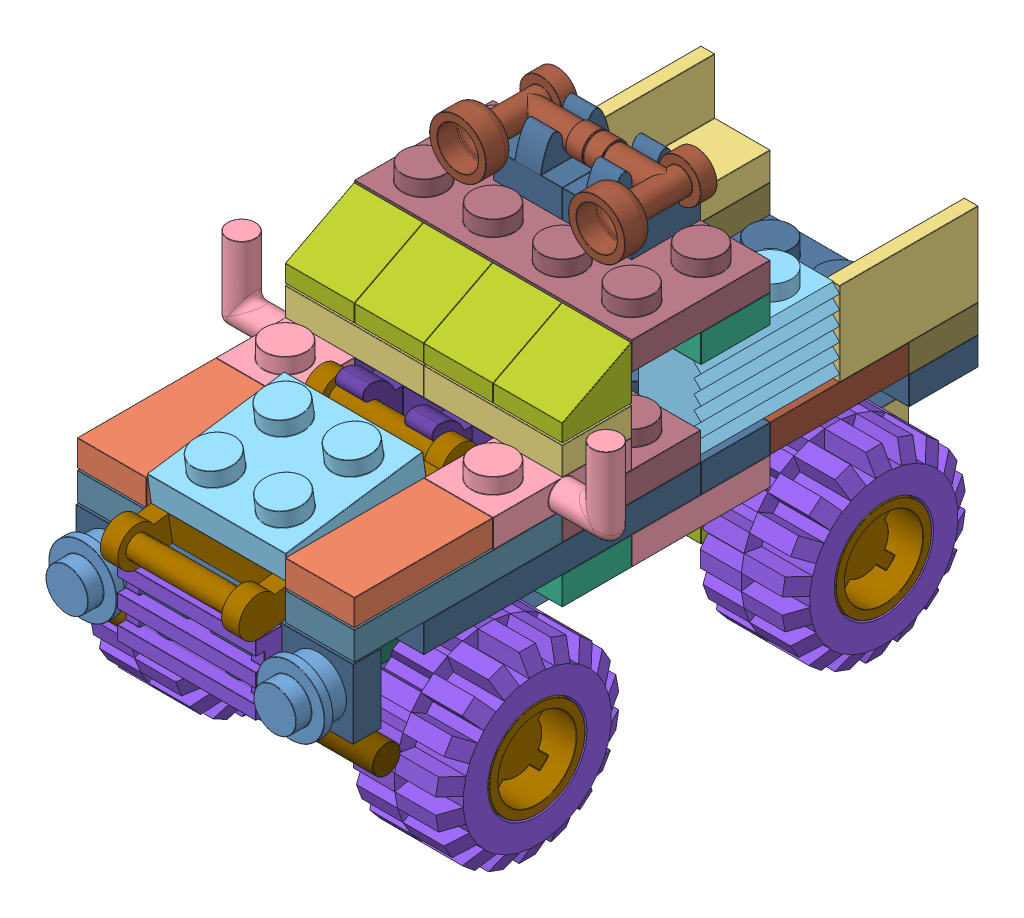
SolidWorks assembly Yellow Truck, configuration Default. Lengths in mm.
Overall size (45.06 54.34 77.31).
66 component instances, 29 part files, 149 mates.
Components (placement in the parent):
- 4211406-1: 4211406 [Default] at (-6.4803 -11.5963 11.298) size (15.92 5.02 63.68)
- 379526-1: 379526 [Default] at (-14.4403 -8.3763 3.338) size (15.92 5.02 47.76)
- 302326-1: 302326 [Default] at (-14.4403 -8.3763 -44.422) size (15.92 5.02 7.96)
- 4211094-1: 4211094 [Default] at (-22.4003 -5.1563 -12.582) size (15.92 5.02 15.92)
- 4211094-2: 4211094 [Default] at (-6.4803 -5.1563 -12.582) size (15.92 5.02 15.92)
- 302224-1: 302224 [Default] at (-14.4403 -5.1563 -28.502) size (15.92 5.02 15.92)
- 4210635-1: 4210635 [Default] at (-14.4403 -5.1563 -4.622) x (-1 0 0) z (0 0 -1) size (15.92 5.02 15.92)
- 4210635-2: 4210635 [Default] at (-6.4803 -5.1563 -4.622) x (0 0 1) z (-1 0 0) size (15.92 5.02 15.92)
- Wheel Assembly-1: Wheel Assembly [Default] at (-7.1213 -14.0712 6.9296) size (42 29.52 29.52)
  - 4211504-1: 4211504 [Default] at (-7.319 -0.7451 4.3684) size (27.68 6.09 15.92)
  - 4514560-1: 4514560 [Default] at (-18.469 0.3282 0.3884) x (1 0 0) z (0 -0.782052 0.623213) size (11.74 21 21)
  - 4514560-2: 4514560 [Default] at (11.791 0.3282 0.3884) size (11.74 21 21)
  - 4170457-1: 4170457 [Default] at (-12.499 0.3282 0.3884) x (0 1 0) z (0 0 1) size (11 11.84 11)
  - 4170457-2: 4170457 [Default] at (5.821 0.3282 0.3884) x (0 -1 0) z (0 0 1) size (11 11.84 11)
- Wheel Assembly-2: Wheel Assembly [Default] at (-7.1213 -14.0712 -32.8704) size (42 29.52 29.52)
  - 4211504-1: 4211504 [Default] at (-7.319 -0.7451 4.3684) size (27.68 6.09 15.92)
  - 4514560-1: 4514560 [Default] at (-18.469 0.3282 0.3884) x (1 0 0) z (0 -0.782052 0.623213) size (11.74 21 21)
  - 4514560-2: 4514560 [Default] at (11.791 0.3282 0.3884) size (11.74 21 21)
  - 4170457-1: 4170457 [Default] at (-12.499 0.3282 0.3884) x (0 1 0) z (0 0 1) size (11 11.84 11)
  - 4170457-2: 4170457 [Default] at (5.821 0.3282 0.3884) x (0 -1 0) z (0 0 1) size (11 11.84 11)
- 302326-2: 302326 [Default] at (-14.4403 -14.8163 -44.422) size (15.92 5.02 7.96)
- 4211001-1: 4211001 [Default] at (-22.4003 -5.1563 -44.422) size (31.84 5.02 7.96)
- 302224-2: 302224 [Default] at (-14.4403 -1.9363 -4.622) size (15.92 5.02 15.92)
- 4211001-2: 4211001 [Default] at (-22.4003 -1.9363 -20.542) size (31.84 5.02 7.96)
- 4211065-1: 4211065 [Default] at (-22.4003 -1.9363 -28.502) size (31.84 5.02 15.92)
- 3000841-1: 3000841 [Default] at (-22.4003 -1.9363 -44.422) size (7.96 5.02 7.96)
- 3000841-2: 3000841 [Default] at (1.4797 -1.9363 -44.422) size (7.96 5.02 7.96)
- 4211001-3: 4211001 [Default] at (-22.4003 -1.9363 11.298) x (0 0 -1) z (1 0 0) size (31.84 5.02 7.96)
- 4211001-4: 4211001 [Default] at (1.4797 -1.9363 11.298) x (0 0 -1) z (1 0 0) size (31.84 5.02 7.96)
- 302024-1: 302024 [Default] at (-22.4003 1.2837 -4.622) size (31.84 5.02 15.92)
- 362324-1: 362324 [Default] at (-22.4003 1.2837 19.258) x (0 0 -1) z (1 0 0) size (23.88 5.02 7.96)
- 362324-2: 362324 [Default] at (1.4797 1.2837 19.258) x (0 0 -1) z (1 0 0) size (23.88 5.02 7.96)
- 407026-1: 407026 [Default] at (-6.4803 -8.3763 11.298) x (0 0 -1) z (1 0 0) size (7.96 11.34 7.96)
- 407026-2: 407026 [Default] at (-14.4403 -8.3763 11.298) x (0 0 -1) z (1 0 0) size (7.96 11.34 7.96)
- 4211525-1: 4211525 [Default] at (-6.4803 -2.8163 13.723) x (1 0 0) z (0 -1 0) size (7.8 5.02 7.8)
- 4211525-2: 4211525 [Default] at (-14.4403 -2.8163 13.723) x (0.936861 0.349703 0) z (0.349703 -0.936861 0) size (7.8 5.02 7.8)
- 4519849-1: 4519849 [Default] at (-14.4403 -2.8163 16.943) x (1 0 0) z (0 -1 0) size (15.92 6 12.56)
- 4211628-1: 4211628 [Default] at (-26.9803 -10.5463 19.193) x (0 -0.615473 -0.788158) z (0 -0.788158 0.615473) size (3.2 32.1 3.2)
- 4211001-5: 4211001 [Default] at (-22.4003 -2.8163 20.163) x (1 0 0) z (0 -1 0) size (31.84 5.02 7.96)
- 3005744-1: 3005744 [Default] at (-22.4003 -2.8163 23.383) x (1 0 0) z (0 -1 0) size (7.8 5.02 7.8)
- 3005744-2: 3005744 [Default] at (1.4797 -2.8163 23.383) x (1 0 0) z (0 -1 0) size (7.8 5.02 7.8)
- 306924-1: 306924 [Default] at (1.4797 4.5037 11.298) x (0 0 1) z (-1 0 0) size (15.92 3.22 7.96)
- 306924-2: 306924 [Default] at (-22.4003 4.5037 11.298) x (0 0 1) z (-1 0 0) size (15.92 3.22 7.96)
- 4519849-2: 4519849 [Default] at (-14.4403 4.5037 -4.622) size (15.92 6 12.56)
- 486524-1: 486524 [Default] at (1.4797 1.2837 -44.422) x (0 0 1) z (-1 0 0) size (15.92 9.6 7.96)
- 486524-2: 486524 [Default] at (-22.4003 1.2837 -36.462) x (0 0 -1) z (1 0 0) size (15.92 9.6 7.96)
- 4501109-1: 4501109 [Default] at (-22.4003 4.5037 -4.622) x (0 0 1) z (-1 0 0) size (15.92 9.46 14.57)
- 4501109-2: 4501109 [Default] at (1.4797 4.5037 3.338) x (0 0 -1) z (1 0 0) size (15.92 9.46 14.57)
- 302326-3: 302326 [Default] at (-14.4403 7.7237 -4.622) x (-1 0 0) z (0 0 -1) size (15.92 5.02 7.96)
- 302326-4: 302326 [Default] at (-6.4803 7.7237 -4.622) size (15.92 5.02 7.96)
- 287724-1: 287724 [Default] at (-22.4003 1.2837 -28.502) x (0 0 1) z (-1 0 0) size (15.92 11.5 7.96)
- 287724-2: 287724 [Default] at (1.4797 1.2837 -20.542) x (0 0 -1) z (1 0 0) size (15.92 11.5 7.96)
- 371024-1: 371024 [Default] at (-22.4003 10.9837 -20.542) size (31.84 5.02 7.96)
- 302024-2: 302024 [Default] at (-22.4003 14.2037 -12.582) size (31.84 5.02 15.92)
- 4244368-1: 4244368 [Default] at (1.4797 10.9437 -4.622) size (7.96 6.27 7.96)
- 4244368-2: 4244368 [Default] at (-6.4803 10.9437 -4.622) size (7.96 6.27 7.96)
- 4244368-3: 4244368 [Default] at (-14.4403 10.9437 -4.622) size (7.96 6.27 7.96)
- 4244368-4: 4244368 [Default] at (-22.4003 10.9437 -4.622) size (7.96 6.27 7.96)
- 4211350-3: 4211350 [Default] at (-14.4403 -2.8163 23.383) x (1 0 0) z (0 -1 0) size (15.92 3.22 7.96)
- 4244627-1: 4244627 [Default] at (-14.4403 2.2891 18.3167) x (1 0 0) z (0 -0.142613 0.989779) size (15.92 5.02 13.96)
- 4244627-2: 4244627 [Default] at (-6.4803 3.4243 10.4381) x (-1 0 0) z (0 0.142613 -0.989779) size (15.92 5.02 13.96)
- 302224-3: 302224 [Default] at (-14.4403 5.4761 18.7759) x (1 0 0) z (0 -0.142613 0.989779) size (15.92 5.02 15.92)
- 4211069-1: 4211069 [Default] at (-14.4403 17.4237 -20.542) x (0 0 -1) z (1 0 0) size (8.47 6.96 7.96)
- 4211069-2: 4211069 [Default] at (-6.4803 17.4237 -20.542) x (0 0 -1) z (1 0 0) size (8.47 6.96 7.96)
- 4211503-1: 4211503 [Default] at (-18.4403 22.5937 -12.522) x (0 -1 0) z (1 0 0) size (6.5 11.42 11.15)
- 4211503-2: 4211503 [Default] at (-2.4803 22.5937 -12.522) x (0 1 0) z (-1 0 0) size (6.5 11.42 11.15)
Mates (geometry in assembly coordinates):
- Coincident1: coincident aligned: plane of 4211406-1 through (-2.5003 -8.3763 7.318) normal (1 0 0); plane of 379526-1 through (-2.5003 -5.1563 -0.642) normal (1 0 0)
- Distance1: distance = 7.96 mm aligned: plane of 379526-1 through (-18.4203 -5.1563 7.318) normal (0 0 1); plane of 4211406-1 through (-10.4603 -8.3763 15.278) normal (0 0 1)
- Coincident3: coincident anti-aligned: plane of 4211406-1 through (-2.5003 -8.3763 15.278) normal (0 1 0); plane of 379526-1 through (-10.4603 -8.3763 7.318) normal (0 -1 0)
- Coincident4: coincident aligned: plane of 4211406-1 through (-2.5003 -8.3763 7.318) normal (1 0 0); plane of 302326-1 through (-2.5003 -5.1563 -48.402) normal (1 0 0)
- Coincident5: coincident aligned: plane of 4211406-1 through (-10.4603 -8.3763 -48.402) normal (0 0 -1); plane of 302326-1 through (-18.4203 -5.1563 -48.402) normal (0 0 -1)
- Coincident6: coincident anti-aligned: plane of 4211406-1 through (-2.5003 -8.3763 15.278) normal (0 1 0); plane of 302326-1 through (-10.4603 -8.3763 -40.442) normal (0 -1 0)
- Coincident10: coincident anti-aligned: plane of 379526-1 through (-10.4603 -5.1563 7.318) normal (0 1 0); plane of 4211094-2 through (-2.5003 -5.1563 -8.602) normal (0 -1 0)
- Concentric3: concentric aligned: cylinder of 379526-1; cylinder of 4211094-2
- Concentric4: concentric aligned: cylinder of 379526-1; cylinder of 4211094-2
- Concentric5: concentric aligned: cylinder of 379526-1; cylinder of 4211094-1
- Concentric6: concentric aligned: cylinder of 379526-1; cylinder of 4211094-1
- Coincident11: coincident anti-aligned: plane of 379526-1 through (-10.4603 -5.1563 7.318) normal (0 1 0); plane of 4211094-1 through (-18.4203 -5.1563 -8.602) normal (0 -1 0)
- Concentric7: concentric aligned: cylinder of 379526-1; cylinder of 302224-1
- Concentric8: concentric aligned: cylinder of 379526-1; cylinder of 302224-1
- Coincident12: coincident anti-aligned: plane of 379526-1 through (-10.4603 -5.1563 7.318) normal (0 1 0); plane of 302224-1 through (-10.4603 -5.1563 -24.522) normal (0 -1 0)
- Concentric9: concentric aligned: cylinder of 379526-1; cylinder of 4210635-2
- Concentric10: concentric aligned: cylinder of 379526-1; cylinder of 4210635-2
- Coincident13: coincident anti-aligned: plane of 379526-1 through (-10.4603 -5.1563 7.318) normal (0 1 0); plane of 4210635-2 through (-10.4603 -5.1563 -0.642) normal (0 -1 0)
- Concentric11: concentric aligned: cylinder of 379526-1; cylinder of 4210635-1
- Concentric12: concentric aligned: cylinder of 379526-1; cylinder of 4210635-1
- Coincident14: coincident anti-aligned: plane of 379526-1 through (-10.4603 -5.1563 7.318) normal (0 1 0); plane of 4210635-1 through (-18.4203 -5.1563 -8.602) normal (0 -1 0)
- Concentric13: concentric aligned: cylinder of 4211406-1; cylinder of Wheel Assembly-1/4211504-1
- Concentric14: concentric aligned: cylinder of 4211406-1; cylinder of Wheel Assembly-1/4211504-1
- Coincident15: coincident anti-aligned: plane of 4211406-1 through (-2.5003 -11.5963 15.278) normal (0 -1 0); plane of Wheel Assembly-1/4211504-1 through (-10.4603 -11.5963 15.278) normal (0 1 0)
- Concentric15: concentric aligned: cylinder of 302326-1; cylinder of 302326-2
- Concentric16: concentric aligned: cylinder of 302326-1; cylinder of 302326-2
- Coincident16: coincident anti-aligned: plane of 4211406-1 through (-2.5003 -11.5963 15.278) normal (0 -1 0); plane of 302326-2 through (-10.4603 -11.5963 -40.442) normal (0 1 0)
- Concentric17: concentric aligned: cylinder of 302224-1; cylinder of Wheel Assembly-2/4211504-1
- Concentric18: concentric aligned: cylinder of 302224-1; cylinder of Wheel Assembly-2/4211504-1
- Coincident17: coincident anti-aligned: plane of 4211406-1 through (-2.5003 -11.5963 15.278) normal (0 -1 0); plane of Wheel Assembly-2/4211504-1 through (-10.4603 -11.5963 -24.522) normal (0 1 0)
- Concentric19: concentric aligned: cylinder of 302326-1; cylinder of 4211001-1
- Concentric20: concentric aligned: cylinder of 302326-1; cylinder of 4211001-1
- Coincident18: coincident anti-aligned: plane of 302326-1 through (-10.4603 -5.1563 -40.442) normal (0 1 0); plane of 4211001-1 through (-18.4203 -5.1563 -40.442) normal (0 -1 0)
- Concentric21: concentric aligned: cylinder of 4211094-2; cylinder of 4211001-2
- Concentric22: concentric aligned: cylinder of 4211094-1; cylinder of 4211001-2
- Coincident19: coincident anti-aligned: plane of 4211094-1 through (-18.4203 -1.9363 -8.602) normal (0 1 0); plane of 4211001-2 through (-18.4203 -1.9363 -16.562) normal (0 -1 0)
- Concentric23: concentric aligned: cylinder of 4211094-2; cylinder of 302224-2
- Concentric24: concentric aligned: cylinder of 4210635-1; cylinder of 302224-2
- Coincident20: coincident anti-aligned: plane of 4210635-2 through (-10.4603 -1.9363 -0.642) normal (0 1 0); plane of 302224-2 through (-10.4603 -1.9363 -0.642) normal (0 -1 0)
- Concentric25: concentric aligned: cylinder of 302224-1; cylinder of 4211065-1
- Concentric26: concentric aligned: cylinder of 302224-1; cylinder of 4211065-1
- Coincident21: coincident anti-aligned: plane of 302224-1 through (-10.4603 -1.9363 -24.522) normal (0 1 0); plane of 4211065-1 through (-18.4203 -1.9363 -24.522) normal (0 -1 0)
- Concentric27: concentric aligned: cylinder of 4211001-1; cylinder of 3000841-2
- Coincident22: coincident aligned: plane of 4211001-1 through (5.4597 -1.9363 -48.402) normal (1 0 0); plane of 3000841-2 through (5.4597 1.2837 -48.402) normal (1 0 0)
- Coincident23: coincident anti-aligned: plane of 4211001-1 through (-18.4203 -1.9363 -40.442) normal (0 1 0); plane of 3000841-2 through (5.4597 -1.9363 -40.442) normal (0 -1 0)
- Concentric28: concentric aligned: cylinder of 4211001-1; cylinder of 3000841-1
- Coincident24: coincident aligned: plane of 4211001-1 through (-26.3803 -1.9363 -48.402) normal (-1 0 0); plane of 3000841-1 through (-26.3803 1.2837 -48.402) normal (-1 0 0)
- Coincident25: coincident anti-aligned: plane of 4211001-1 through (-18.4203 -1.9363 -40.442) normal (0 1 0); plane of 3000841-1 through (-18.4203 -1.9363 -40.442) normal (0 -1 0)
- Concentric29: concentric aligned: cylinder of 4211094-2; cylinder of 4211001-4
- Concentric30: concentric aligned: cylinder of 4210635-2; cylinder of 4211001-4
- Concentric31: concentric aligned: cylinder of 4211094-1; cylinder of 4211001-3
- Concentric32: concentric aligned: cylinder of 4210635-1; cylinder of 4211001-3
- Coincident26: coincident anti-aligned: plane of 4211094-1 through (-18.4203 -1.9363 -8.602) normal (0 1 0); plane of 4211001-3 through (-18.4203 -1.9363 7.318) normal (0 -1 0)
- Coincident27: coincident anti-aligned: plane of 4211094-2 through (-2.5003 -1.9363 -8.602) normal (0 1 0); plane of 4211001-4 through (5.4597 -1.9363 7.318) normal (0 -1 0)
- Concentric33: concentric aligned: cylinder of 4211001-4; cylinder of 302024-1
- Concentric34: concentric aligned: cylinder of 4211001-3; cylinder of 302024-1
- Coincident28: coincident anti-aligned: plane of 302224-2 through (-10.4603 1.2837 -0.642) normal (0 1 0); plane of 302024-1 through (-18.4203 1.2837 -0.642) normal (0 -1 0)
- Concentric35: concentric aligned: cylinder of 4211001-4; cylinder of 362324-2
- Concentric36: concentric aligned: cylinder of 4211001-4; cylinder of 362324-2
- Concentric37: concentric aligned: cylinder of 4211001-3; cylinder of 362324-1
- Concentric38: concentric aligned: cylinder of 4211001-3; cylinder of 362324-1
- Coincident29: coincident anti-aligned: plane of 4211001-3 through (-18.4203 1.2837 7.318) normal (0 1 0); plane of 362324-1 through (-18.4203 1.2837 15.278) normal (0 -1 0)
- Coincident30: coincident anti-aligned: plane of 4211001-4 through (5.4597 1.2837 7.318) normal (0 1 0); plane of 362324-2 through (5.4597 1.2837 15.278) normal (0 -1 0)
- Concentric39: concentric aligned: cylinder of 4211406-1; cylinder of 407026-2
- Concentric40: concentric aligned: cylinder of 4211406-1; cylinder of 407026-1
- Coincident32: coincident aligned: plane of 4211406-1 through (-10.4603 -8.3763 15.278) normal (0 0 1); plane of 407026-2 through (-18.4203 1.1637 15.278) normal (0 0 1)
- Coincident33: coincident aligned: plane of 4211406-1 through (-10.4603 -8.3763 15.278) normal (0 0 1); plane of 407026-1 through (-10.4603 1.1637 15.278) normal (0 0 1)
- Coincident34: coincident anti-aligned: plane of 4211406-1 through (-2.5003 -8.3763 15.278) normal (0 1 0); plane of 407026-2 through (-10.4603 -8.3763 7.318) normal (0 -1 0)
- Coincident35: coincident anti-aligned: plane of 4211406-1 through (-2.5003 -8.3763 15.278) normal (0 1 0); plane of 407026-1 through (-2.5003 -8.3763 7.318) normal (0 -1 0)
- Concentric41: concentric aligned: cylinder of 4211525-2; cylinder of 407026-2
- Concentric42: concentric aligned: cylinder of 4211525-1; cylinder of 407026-1
- Coincident36: coincident anti-aligned: plane of 407026-2 through (-18.4203 -6.7763 13.723) normal (0 0 1); plane of 4211525-2 through (-14.4403 -2.8163 13.723) normal (0 0 -1)
- Coincident37: coincident anti-aligned: plane of 407026-1 through (-10.4603 -6.7763 13.723) normal (0 0 1); plane of 4211525-1 through (-6.4803 -2.8163 13.723) normal (0 0 -1)
- Concentric43: concentric aligned: cylinder of 4519849-1; cylinder of 4211525-1
- Concentric44: concentric aligned: cylinder of 4211525-2; cylinder of 4519849-1
- Coincident38: coincident anti-aligned: plane of 4211525-2 through (-14.4403 -2.8163 16.943) normal (0 0 1); plane of 4519849-1 through (-10.4603 -6.7963 16.943) normal (0 0 -1)
- Concentric45: concentric anti-aligned: cylinder of 4519849-1; cylinder of 4211628-1
- Distance2: distance = 10 mm aligned: plane of 4519849-1 through (-4.8803 -10.5463 19.193) normal (1 0 0); plane of 4211628-1 through (5.1197 -10.5463 19.193) normal (1 0 0)
- Concentric46: concentric aligned: cylinder of 4211001-5; cylinder of 3005744-2
- Concentric47: concentric aligned: cylinder of 4211001-5; cylinder of 3005744-1
- Coincident39: coincident anti-aligned: plane of 4211001-5 through (-18.4203 -6.7963 23.383) normal (0 0 1); plane of 3005744-1 through (-22.4003 -2.8163 23.383) normal (0 0 -1)
- Coincident40: coincident anti-aligned: plane of 4211001-5 through (-18.4203 -6.7963 23.383) normal (0 0 1); plane of 3005744-2 through (1.4797 -2.8163 23.383) normal (0 0 -1)
- Concentric48: concentric aligned: cylinder of 4211001-5; cylinder of 4519849-1
- Concentric49: concentric aligned: cylinder of 4519849-1; cylinder of 4211001-5
- Coincident41: coincident anti-aligned: plane of 4519849-1 through (-10.4603 -6.7963 20.163) normal (0 0 1); plane of 4211001-5 through (-18.4203 -6.7963 20.163) normal (0 0 -1)
- Coincident43: coincident aligned: plane of 306924-1 through (5.4597 7.7237 23.238) normal (0 0 1); plane of 362324-2 through (-2.5003 4.5037 23.238) normal (0 0 1)
- Coincident44: coincident aligned: plane of 362324-2 through (5.4597 4.5037 23.238) normal (1 0 0); plane of 306924-1 through (5.4597 7.7237 7.318) normal (1 0 0)
- Coincident45: coincident anti-aligned: plane of 362324-2 through (5.4597 4.5037 15.278) normal (0 1 0); plane of 306924-1 through (-2.5003 4.5037 15.278) normal (0 -1 0)
- Coincident46: coincident aligned: plane of 306924-2 through (-18.4203 7.7237 23.238) normal (0 0 1); plane of 362324-1 through (-26.3803 4.5037 23.238) normal (0 0 1)
- Coincident47: coincident aligned: plane of 362324-1 through (-26.3803 4.5037 23.238) normal (-1 0 0); plane of 306924-2 through (-26.3803 7.7237 7.318) normal (-1 0 0)
- Coincident48: coincident anti-aligned: plane of 362324-1 through (-18.4203 4.5037 15.278) normal (0 1 0); plane of 306924-2 through (-26.3803 4.5037 15.278) normal (0 -1 0)
- Concentric50: concentric aligned: cylinder of 302024-1; cylinder of 4519849-2
- Concentric51: concentric aligned: cylinder of 302024-1; cylinder of 4519849-2
- Coincident49: coincident anti-aligned: plane of 302024-1 through (-18.4203 4.5037 -0.642) normal (0 1 0); plane of 4519849-2 through (-10.4603 4.5037 -0.642) normal (0 -1 0)
- Coincident50: coincident aligned: plane of 486524-2 through (-26.3803 4.5037 -48.402) normal (0 0 -1); plane of 3000841-1 through (-26.3803 1.2837 -48.402) normal (0 0 -1)
- Coincident51: coincident aligned: plane of 486524-1 through (5.4597 4.5037 -48.402) normal (0 0 -1); plane of 3000841-2 through (-2.5003 1.2837 -48.402) normal (0 0 -1)
- Coincident52: coincident aligned: plane of 3000841-1 through (-26.3803 1.2837 -48.402) normal (-1 0 0); plane of 486524-2 through (-26.3803 4.5037 -32.482) normal (-1 0 0)
- Coincident53: coincident aligned: plane of 3000841-2 through (5.4597 1.2837 -48.402) normal (1 0 0); plane of 486524-1 through (5.4597 4.5037 -48.402) normal (1 0 0)
- Coincident54: coincident anti-aligned: plane of 4211065-1 through (-18.4203 1.2837 -24.522) normal (0 1 0); plane of 486524-1 through (-2.5003 1.2837 -40.442) normal (0 -1 0)
- Coincident55: coincident anti-aligned: plane of 4211065-1 through (-18.4203 1.2837 -24.522) normal (0 1 0); plane of 486524-2 through (-18.4203 1.2837 -40.442) normal (0 -1 0)
- Concentric52: concentric aligned: cylinder of 302024-1; cylinder of 4501109-2
- Concentric53: concentric aligned: cylinder of 362324-2; cylinder of 4501109-2
- Concentric54: concentric aligned: cylinder of 362324-1; cylinder of 4501109-1
- Concentric55: concentric aligned: cylinder of 302024-1; cylinder of 4501109-1
- Coincident56: coincident anti-aligned: plane of 362324-2 through (5.4597 4.5037 15.278) normal (0 1 0); plane of 4501109-2 through (5.4597 4.5037 -0.642) normal (0 -1 0)
- Coincident57: coincident anti-aligned: plane of 362324-1 through (-18.4203 4.5037 15.278) normal (0 1 0); plane of 4501109-1 through (-26.3803 4.5037 -0.642) normal (0 -1 0)
- Concentric56: concentric aligned: cylinder of 4501109-2; cylinder of 302326-4
- Concentric58: concentric aligned: cylinder of 4501109-1; cylinder of 302326-3
- Concentric59: concentric aligned: cylinder of 4519849-2; cylinder of 302326-3
- Concentric60: concentric aligned: cylinder of 4519849-2; cylinder of 302326-4
- Coincident58: coincident anti-aligned: plane of 4501109-2 through (5.4597 7.7237 -0.642) normal (0 1 0); plane of 302326-4 through (-2.5003 7.7237 -0.642) normal (0 -1 0)
- Coincident59: coincident anti-aligned: plane of 4519849-2 through (-10.4603 7.7237 -0.642) normal (0 1 0); plane of 302326-3 through (-18.4203 7.7237 -8.602) normal (0 -1 0)
- Concentric61: concentric aligned: cylinder of 4211065-1; cylinder of 287724-2
- Concentric62: concentric aligned: cylinder of 4211001-2; cylinder of 287724-2
- Concentric63: concentric aligned: cylinder of 4211065-1; cylinder of 287724-1
- Concentric64: concentric aligned: cylinder of 4211001-2; cylinder of 287724-1
- Coincident60: coincident anti-aligned: plane of 4211065-1 through (-18.4203 1.2837 -24.522) normal (0 1 0); plane of 287724-1 through (-26.3803 1.2837 -24.522) normal (0 -1 0)
- Coincident61: coincident anti-aligned: plane of 4211001-2 through (-18.4203 1.2837 -16.562) normal (0 1 0); plane of 287724-2 through (5.4597 1.2837 -24.522) normal (0 -1 0)
- Concentric65: concentric aligned: cylinder of 287724-2; cylinder of 371024-1
- Concentric66: concentric aligned: cylinder of 287724-1; cylinder of 371024-1
- Coincident62: coincident anti-aligned: plane of 287724-2 through (5.4597 10.9837 -24.522) normal (0 1 0); plane of 371024-1 through (-18.4203 10.9837 -16.562) normal (0 -1 0)
- Concentric67: concentric aligned: cylinder of 371024-1; cylinder of 302024-2
- Concentric68: concentric aligned: cylinder of 371024-1; cylinder of 302024-2
- Coincident63: coincident anti-aligned: plane of 371024-1 through (-18.4203 14.2037 -16.562) normal (0 1 0); plane of 302024-2 through (-18.4203 14.2037 -8.602) normal (0 -1 0)
- Coincident64: coincident aligned: plane of 302326-4 through (5.4597 10.9437 -8.602) normal (1 0 0); plane of 4244368-1 through (5.4597 17.2437 -8.602) normal (1 0 0)
- Coincident65: coincident aligned: plane of 302326-4 through (-10.4603 10.9437 -0.642) normal (0 0 1); plane of 4244368-1 through (-2.5003 17.2437 -0.642) normal (0 0 1)
- Coincident66: coincident anti-aligned: plane of 302326-4 through (-2.5003 10.9437 -0.642) normal (0 1 0); plane of 4244368-1 through (5.4597 10.9437 -0.642) normal (0 -1 0)
- Coincident67: coincident aligned: plane of 4211350-3 through (-18.4203 -6.7963 26.603) normal (0 -1 0); plane of 4211001-5 through (-26.3803 -6.7963 23.383) normal (0 -1 0)
- Distance3: distance = 7.96 mm aligned: plane of 4211350-3 through (-2.5003 1.1637 26.603) normal (1 0 0); plane of 4211001-5 through (5.4597 1.1637 23.383) normal (1 0 0)
- Coincident69: coincident anti-aligned: plane of 4211001-5 through (-18.4203 -6.7963 23.383) normal (0 0 1); plane of 4211350-3 through (-10.4603 -6.7963 23.383) normal (0 0 -1)
- Concentric69: concentric aligned: cylinder of 4244627-1; cylinder of 302224-3
- Concentric70: concentric aligned: cylinder of 4244627-1; cylinder of 302224-3
- Coincident70: coincident anti-aligned: plane of 4244627-1 through (-10.4603 4.9085 22.7153) normal (0 0.989779 0.142613); plane of 302224-3 through (-10.4603 4.9085 22.7153) normal (0 -0.989779 -0.142613)
- Concentric71: concentric aligned: cylinder of 4244627-2; cylinder of 302224-3
- Concentric72: concentric aligned: cylinder of 4244627-2; cylinder of 302224-3
- Coincident71: coincident anti-aligned: plane of 4244627-2 through (-10.4603 7.1789 6.958) normal (0 0.989779 0.142613); plane of 302224-3 through (-10.4603 4.9085 22.7153) normal (0 -0.989779 -0.142613)
- Concentric73: concentric aligned: cylinder of 4519849-2; cylinder of 4244627-2
- Coincident72: coincident anti-aligned: plane of 306924-2 through (-18.4203 7.7237 7.318) normal (1 0 0); plane of 302224-3 through (-18.4203 9.2308 15.2958) normal (-1 0 0)
- Tangent1: tangent anti-aligned: plane of 4211350-3 through (-18.4203 1.1637 26.603) normal (0 1 0); cylinder of 4244627-1
- Distance4: distance = 15.92 mm anti-aligned: plane of 4211069-1 through (-10.4603 20.6437 -16.562) normal (1 0 0); plane of 302024-2 through (-26.3803 17.4237 -16.562) normal (-1 0 0)
- Coincident74: coincident aligned: plane of 302024-2 through (-26.3803 17.4237 -24.522) normal (0 0 -1); plane of 4211069-1 through (-18.4203 20.6437 -24.522) normal (0 0 -1)
- Coincident75: coincident anti-aligned: plane of 302024-2 through (-18.4203 17.4237 -8.602) normal (0 1 0); plane of 4211069-1 through (-10.4603 17.4237 -24.522) normal (0 -1 0)
- Concentric74: concentric anti-aligned: cylinder of 4211069-1; cylinder of 4211503-1
- Parallel1: parallel aligned: plane of 4211069-1 through (-18.4203 20.6437 -24.522) normal (0 0 -1); plane of 4211503-1 through (-18.4403 22.5937 -23.942) normal (0 0 -1)
- Distance5: distance = 0.5 mm anti-aligned: plane of 4211069-1 through (-12.9403 23.5476 -17.5017) normal (1 0 0); plane of 4211503-1 through (-12.4403 22.5937 -20.542) normal (-1 0 0)
- Parallel2: parallel aligned: plane of 302024-2 through (-26.3803 17.4237 -24.522) normal (0 0 -1); plane of 4211503-2 through (-2.4803 22.5937 -23.942) normal (0 0 -1)
- Concentric75: concentric aligned: cylinder of 4211069-2; cylinder of 4211503-2
- Distance7: distance = 0.5 mm anti-aligned: unknown of 4211069-2; unknown of 4211503-2
- LocalLPattern2: unknown: unknown of 302024-2
